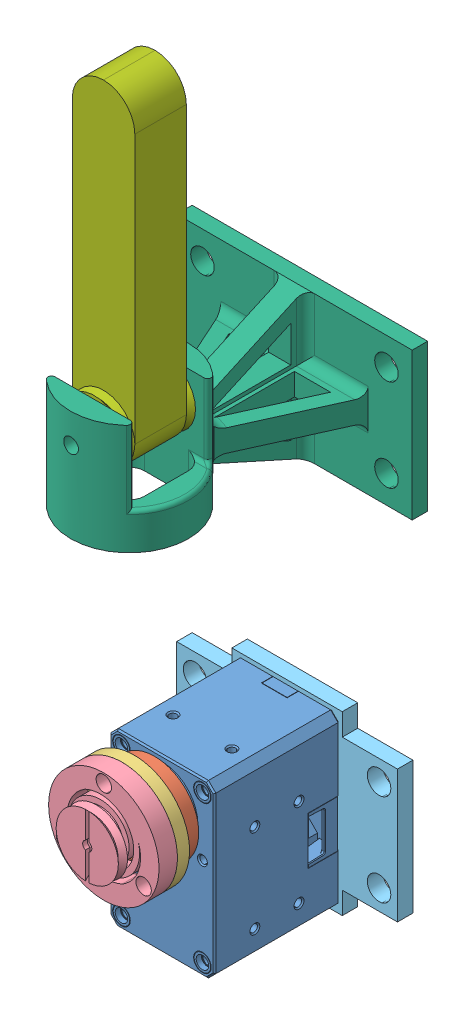
SolidWorks assembly exp_rod, configuration 기본. Lengths in mm.
Overall size (64 216.08 65).
7 component instances, 7 part files, 16 mates.
Components (placement in the parent):
- xm-430_idle(stp)-1: xm-430_idle(stp) [기본] at (-8.3249 8.7981 44.3001) size (28.5 46.5 42.4)
- SEA_motor_v5-1: SEA_motor_v5 [기본] at (-8.3249 8.7981 63.3001) size (24 24 5.5)
- SEA_pulley_v5_part1-1: SEA_pulley_v5_part1 [기본] at (-8.3249 8.7981 68.8001) size (30 29.39 3.3)
- SEA_pulley_v6_part2-1: SEA_pulley_v6_part2 [기본] at (-8.3249 8.7981 72.1001) size (30 30 9.5)
- motor_hold-1: motor_hold [기본] at (-8.3249 -3.2019 23.1001) size (60 48 4.2)
- rod_hold-1: rod_hold [기본] at (-6.3249 95.3811 23.1001) x (0 -1 0) z (0 0 1) size (40 64 65)
- rod-1: rod [기본] at (-6.3249 143.8811 72.1724) size (17 90 19)
Mates (geometry in assembly coordinates):
- 동심1: concentric anti-aligned: circle of xm-430_idle(stp)-1; circle of SEA_motor_v5-1
- 일치1: coincident anti-aligned: plane of xm-430_idle(stp)-1 through (-8.3249 8.7981 63.3001) normal (0 0 1); plane of SEA_motor_v5-1 through (-8.3249 8.7981 63.3001) normal (0 0 -1)
- 동심2: concentric aligned: cylinder of xm-430_idle(stp)-1 through (-8.3249 16.7981 60.6954) axis (0 0 1) radius 0.8; cylinder of SEA_motor_v5-1 through (-8.3249 16.7981 57.3604) axis (0 0 1) radius 2.1
- 동심3: concentric aligned: cylinder of SEA_motor_v5-1 through (-8.3249 8.7981 68.8001) axis (0 0 -1) radius 12; cylinder of SEA_pulley_v5_part1-1 through (-8.3249 8.7981 72.1001) axis (0 0 -1) radius 15
- 동심4: concentric aligned: cylinder of SEA_motor_v5-1 through (-1.6074 15.5156 68.8001) axis (0 0 -1) radius 1; cylinder of SEA_pulley_v5_part1-1 through (-1.6074 15.5156 72.1001) axis (0 0 -1) radius 1.1
- 일치2: coincident anti-aligned: plane of SEA_motor_v5-1 through (-8.3249 8.7981 68.8001) normal (0 0 1); plane of SEA_pulley_v5_part1-1 through (-8.3249 8.7981 68.8001) normal (0 0 -1)
- 동심5: concentric aligned: cylinder of SEA_pulley_v5_part1-1 through (-8.3249 8.7981 72.1001) axis (0 0 -1) radius 15; cylinder of SEA_pulley_v6_part2-1 through (-8.3249 8.7981 73.5001) axis (0 0 -1) radius 15
- 동심6: concentric aligned: cylinder of SEA_pulley_v5_part1-1 through (-8.3249 21.2981 72.1001) axis (0 0 -1) radius 1; cylinder of SEA_pulley_v6_part2-1 through (-8.3249 21.2981 77.1001) axis (0 0 -1) radius 2.1
- 일치3: coincident anti-aligned: plane of SEA_pulley_v5_part1-1 through (-8.3249 8.7981 72.1001) normal (0 0 1); plane of SEA_pulley_v6_part2-1 through (-8.3249 8.7981 72.1001) normal (0 0 -1)
- 동심7: concentric anti-aligned: cylinder of xm-430_idle(stp)-1 through (2.6751 16.7981 27.3001) axis (0 0 1) radius 1.7; cylinder of motor_hold-1 through (2.6751 16.7981 27.3001) axis (0 0 -1) radius 1.25
- 동심9: concentric anti-aligned: cylinder of xm-430_idle(stp)-1 through (2.6751 -23.2019 27.3001) axis (0 0 1) radius 1.7; cylinder of motor_hold-1 through (2.6751 -23.2019 27.3001) axis (0 0 -1) radius 1.25
- 일치4: coincident anti-aligned: plane of xm-430_idle(stp)-1 through (-8.3249 8.7981 27.3001) normal (0 0 -1); plane of motor_hold-1 through (-8.3249 -3.2019 27.3001) normal (0 0 1)
- 일치5: coincident aligned: plane of motor_hold-1 through (-8.3249 -3.2019 23.1001) normal (0 0 -1); plane of rod_hold-1 through (-6.3249 95.3811 23.1001) normal (0 0 -1)
- 평행1: parallel aligned: plane of motor_hold-1 through (6.6751 20.7981 27.3001) normal (0 1 0); plane of rod_hold-1 through (-6.3249 115.3811 27.3001) normal (0 1 0)
- 일치7: coincident aligned: plane of motor_hold-1 through (-38.3249 14.7981 27.3001) normal (-1 0 0); plane of rod_hold-1 through (-38.3249 95.3811 27.3001) normal (-1 0 0)
- 동심10: concentric aligned: cylinder of rod_hold-1 through (-6.3249 107.3811 88.1011) axis (0 0 -1) radius 2; cylinder of rod-1 through (-6.3249 107.3811 79.1724) axis (0 0 -1) radius 3.6
